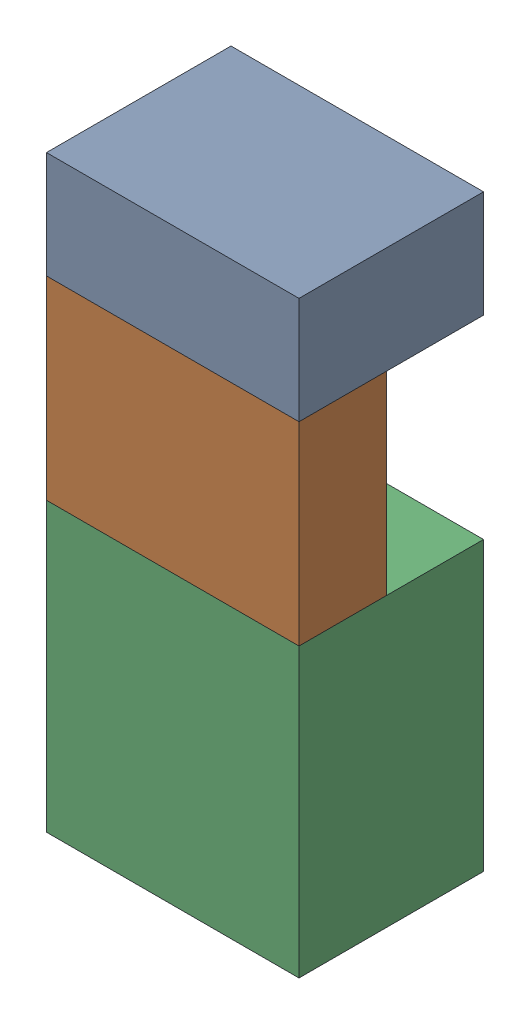
SolidWorks assembly SUP_K10, configuration Default. Lengths in mm.
Overall size (13 30.3 9.5).
6 component instances, 3 part files, 0 mates.
Components (placement in the parent):
- 1151724928-1: 1151724928 [Default] at (144.145 41.975 0) size (13 5.5 9.5)
  - Extruded_2-1: Extruded_2 [Default] at origin size (13 5.5 9.5)
- 1151725064-1: 1151725064 [Default] at (144.145 34.225 5) size (13 10 4.5)
  - Extruded_3-1: Extruded_3 [Default] at origin size (13 10 4.5)
- 1151724792-1: 1151724792 [Default] at (144.145 21.825 0) size (13 14.8 9.5)
  - Extruded_4-1: Extruded_4 [Default] at origin size (13 14.8 9.5)
